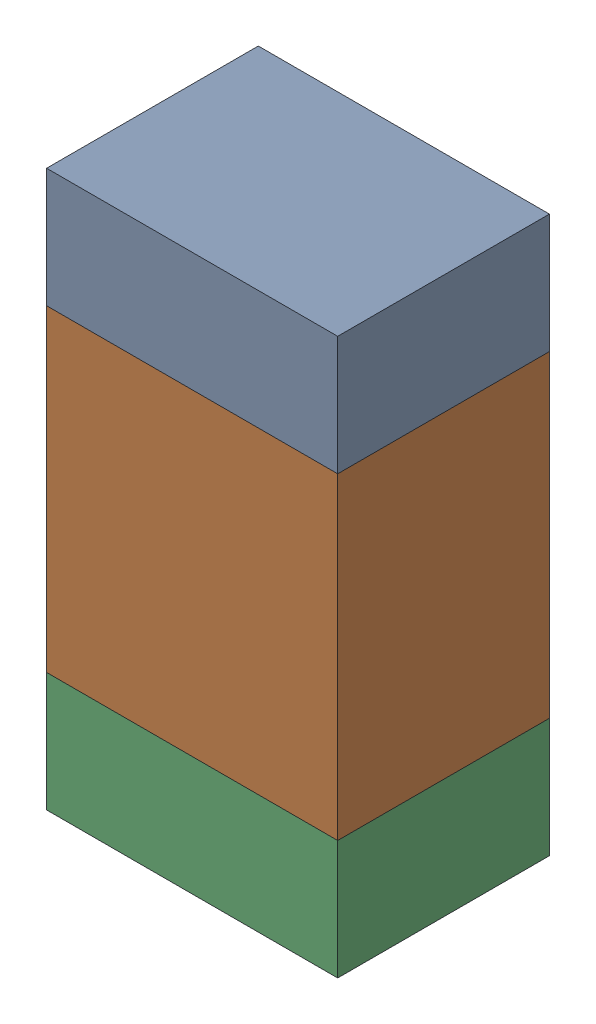
SolidWorks assembly R504_1PCB, configuration Default. Lengths in mm.
Overall size (0.55 1.05 0.4).
6 component instances, 2 part files, 0 mates.
Components (placement in the parent):
- 846483288-1: 846483288 [Default] at (156.8999 121.9126 0) size (0.55 0.22 0.4)
  - Extruded_12-1: Extruded_12 [Default] at origin size (0.55 0.22 0.4)
- 846483424-1: 846483424 [Default] at (156.8999 121.5001 0) size (0.55 0.6 0.4)
  - Extruded_13-1: Extruded_13 [Default] at origin size (0.55 0.6 0.4)
- 846483288-2: 846483288 [Default] at (156.8999 121.0876 0) size (0.55 0.22 0.4)
  - Extruded_12-1: Extruded_12 [Default] at origin size (0.55 0.22 0.4)
